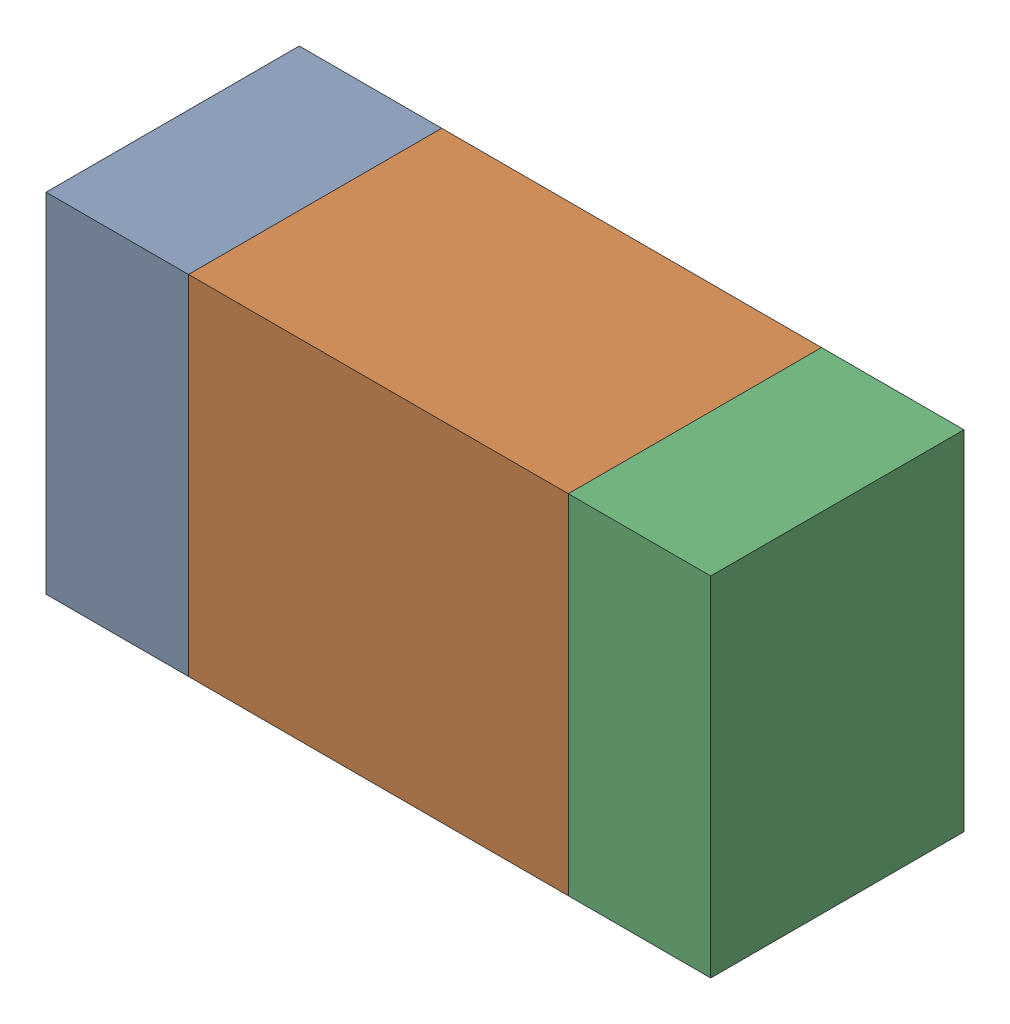
SolidWorks assembly R309_2PCB, configuration Default. Lengths in mm.
Overall size (1.05 0.55 0.4).
6 component instances, 2 part files, 0 mates.
Components (placement in the parent):
- 854785432-1: 854785432 [Default] at (132.7874 92.3001 -2.0638) size (0.22 0.55 0.4)
  - Extruded-1: Extruded [Default] at origin size (0.22 0.55 0.4)
- 854785568-1: 854785568 [Default] at (133.1999 92.3001 -2.0638) size (0.6 0.55 0.4)
  - Extruded_2-1: Extruded_2 [Default] at origin size (0.6 0.55 0.4)
- 854785432-2: 854785432 [Default] at (133.6124 92.3001 -2.0638) size (0.22 0.55 0.4)
  - Extruded-1: Extruded [Default] at origin size (0.22 0.55 0.4)
